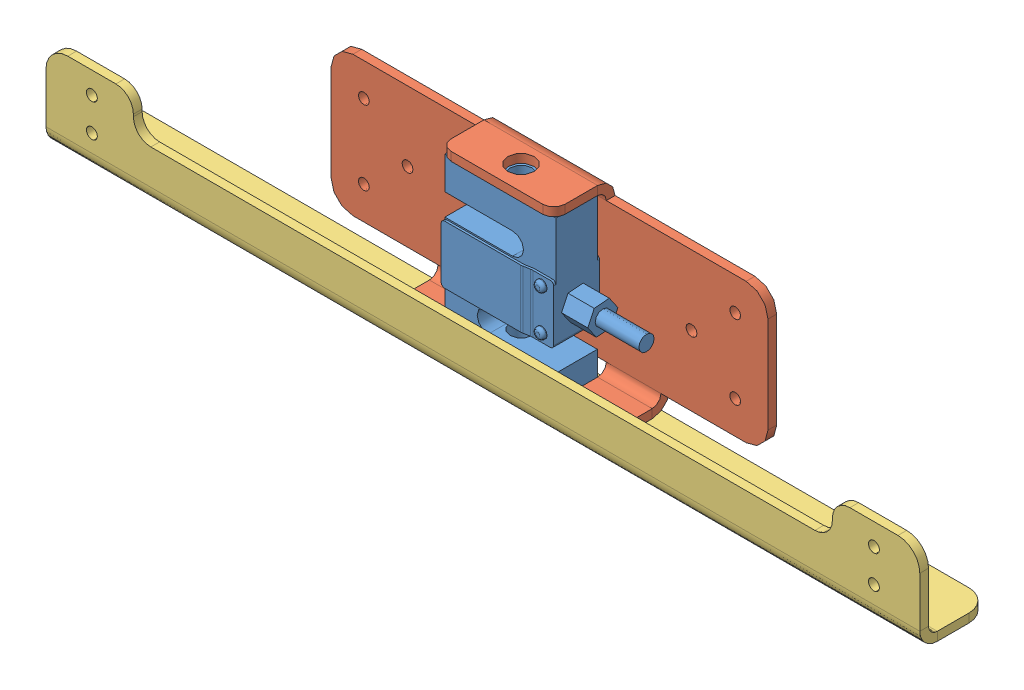
SolidWorks assembly WallBench - Assembly Option 2, configuration Default. Lengths in mm.
Overall size (400 84.5 34.5).
9 component instances, 8 part files, 27 mates.
Components (placement in the parent):
- WallBench - Frame-1: WallBench - Frame [Default] at (-902.6231 586.6756 0) size (560 360 30) (hidden)
- WallBench - Galga-1: WallBench - Galga [Default] at (-902.6231 588.4256 7.5) x (1 0 0) z (0 -1 0) size (82.8 24.7 76.5)
- WallBench - Moving wall-1: WallBench - Moving wall [Default] at (-903.6457 587.3832 38.7366) x (1 0 0) z (0 1 0) size (495 10 295) (hidden)
- Fingerboard-1: Fingerboard [Default] at (-1104.1457 587.3832 58.7366) size (400 99 40) (hidden)
- Tornillo_M12-1: Tornillo_M12 [Default] at (-902.6231 638.6756 17) x (0.845145 0 -0.534536) z (-0.534536 0 -0.845145) size (23.08 23 20.45) (hidden)
- Wall-1: Wall [Default] at (-902.6231 586.6756 -10) x (1 0 0) z (0 -1 0) size (2000 10 1000) (hidden)
- WallBench - Main supoport Option 2-1: WallBench - Main supoport Option 2 [Default] at (-902.6231 590.6756 4) x (1 0 0) z (0 -1 0) size (200 28 80)
- Tornillo_M12-2: Tornillo_M12 [Default] at (-902.6231 534.9122 15) x (0.040349 0 -0.999186) z (0.999186 0 0.040349) size (23.08 23 20.45) (hidden)
- WallBench - L Support-1: WallBench - L Support [Default] at (-902.6231 550.1756 34.75) size (400 41 32.5)
Mates (geometry in assembly coordinates):
- Coincidente1: coincident anti-aligned: plane of WallBench - Frame-1 through (-902.6231 586.6756 0) normal (0 0 -1); plane of assembly through (0 0 0) normal (0 0 1)
- Coincidente2: coincident anti-aligned: plane of WallBench - Frame-1 through (-902.6231 586.6756 0) normal (0 0 -1); plane of Wall-1 through (-902.6231 586.6756 0) normal (0 0 1)
- Distancia1: distance = 320 mm aligned: plane of WallBench - Frame-1 through (-1182.6231 766.6756 30) normal (0 1 0); plane of Wall-1 through (-1902.6231 1086.6756 0) normal (0 1 0)
- Coincidente4: coincident anti-aligned: plane of Wall-1 through (-902.6231 586.6756 0) normal (0 0 1); plane of WallBench - Main supoport Option 2-1 through (-923.6231 645.6756 0) normal (0 0 -1)
- Coincidente5: coincident anti-aligned: plane of WallBench - Galga-1 through (-928.0231 626.6756 26.5) normal (0 1 0); plane of WallBench - Main supoport Option 2-1 through (-923.6231 626.6756 23) normal (0 -1 0)
- Paralelo1: parallel aligned: plane of WallBench - Galga-1 through (-908.2231 570.1756 26.5) normal (0 0 1); plane of WallBench - Main supoport Option 2-1 through (-923.6231 630.6756 28) normal (0 0 1)
- Concéntrica3: concentric anti-aligned: cylinder of WallBench - Galga-1 through (-902.6231 626.6766 17) axis (0 -1 0) radius 5; cylinder of ? through (-902.6231 536.9122 15) axis (0 1 0) radius 6
- Coincidente6: coincident anti-aligned: plane of WallBench - Galga-1 through (-928.0231 550.1756 26.5) normal (0 -1 0); plane of ? through (-1092.6231 546.9122 55) normal (0 1 0)
- Paralelo2: parallel aligned: plane of WallBench - Galga-1 through (-908.2231 570.1756 26.5) normal (0 0 1); plane of ? through (-1092.6231 574.3501 28.7366) normal (0 0 1)
- Coincidente8: coincident: plane of ? through (-1092.6231 574.3501 28.7366) normal (0 0 1); plane of WallBench - Moving wall-1 through (-903.6457 587.3832 28.7366) normal (0 0 -1)
- Coincidente9: coincident anti-aligned: plane of WallBench - Moving wall-1 through (-903.6457 587.3832 38.7366) normal (0 0 1); plane of Fingerboard-1 through (-704.1457 537.8832 38.7366) normal (0 0 -1)
- Concéntrica4: concentric anti-aligned: cylinder of WallBench - Galga-1 through (-902.6231 550.1746 17) axis (0 1 0) radius 5; cylinder of WallBench - Main supoport Option 2-1 through (-902.6231 630.6766 17) axis (0 -1 0) radius 6
- Concéntrica5: concentric anti-aligned: cylinder of Tornillo_M12-1 through (-902.6231 615.6756 17) axis (0 1 0) radius 6; cylinder of WallBench - Main supoport Option 2-1 through (-902.6231 630.6766 17) axis (0 -1 0) radius 6
- Coincidente10: coincident anti-aligned: plane of Tornillo_M12-1 through (-902.6231 630.6756 17) normal (0 -1 0); plane of WallBench - Main supoport Option 2-1 through (-923.6231 630.6756 23) normal (0 1 0)
- Paralelo3: parallel aligned: plane of Tornillo_M12-1 through (-892.6231 630.6756 11.2265) normal (1 0 0); plane of WallBench - Main supoport Option 2-1 through (-876.6231 630.6756 0) normal (1 0 0)
- Concéntrica7: concentric: cylinder of ? through (-902.6231 536.9122 15) axis (0 1 0) radius 6; cylinder of Tornillo_M12-2 through (-902.6231 557.9122 15) axis (0 -1 0) radius 6
- Coincidente12: coincident: plane of ? through (-1092.6231 542.9122 55) normal (0 -1 0); plane of Tornillo_M12-2 through (-902.6231 542.9122 15) normal (0 1 0)
- Perpendicular1: perpendicular: plane of ? through (-1092.6231 574.3501 28.7366) normal (0 0 1); plane of Tornillo_M12-2 through (-892.6231 542.9122 20.7735) normal (1 0 0)
- Distancia2: distance = 720 mm aligned: plane of WallBench - Frame-1 through (-1182.6231 766.6756 30) normal (-1 0 0); plane of Wall-1 through (-1902.6231 1086.6756 0) normal (-1 0 0)
- Distancia5: distance = 150 mm anti-aligned: plane of WallBench - Frame-1 through (-1152.6231 736.6756 30) normal (1 0 0); plane of WallBench - Main supoport Option 2-1 through (-1002.6231 612.6756 0) normal (-1 0 0)
- Distancia6: distance = 114 mm anti-aligned: plane of WallBench - Main supoport Option 2-1 through (-992.6231 622.6756 0) normal (0 1 0); plane of WallBench - Frame-1 through (-1152.6231 736.6756 30) normal (0 -1 0)
- Distancia7: distance = 98 mm aligned: plane of Fingerboard-1 through (-704.1457 636.8832 38.7366) normal (0 1 0); plane of WallBench - Moving wall-1 through (-1151.1457 734.8832 28.7366) normal (0 1 0)
- Distancia8: distance = 47 mm aligned: plane of Fingerboard-1 through (-1104.1457 626.8832 68.7366) normal (-1 0 0); plane of WallBench - Moving wall-1 through (-1151.1457 439.8832 28.7366) normal (-1 0 0)
- Coincidente15: coincident: plane of ? through (-1092.6231 574.3501 28.7366) normal (0 0 1); plane of WallBench - Moving wall-1 through (-903.6457 587.3832 28.7366) normal (0 0 -1)
- Concéntrica8: concentric anti-aligned: cylinder of WallBench - Galga-1 through (-902.6231 626.6766 17) axis (0 -1 0) radius 5; cylinder of WallBench - L Support-1 through (-902.6231 540.1756 17) axis (0 1 0) radius 7
- Coincidente16: coincident anti-aligned: plane of WallBench - Galga-1 through (-928.0231 550.1756 26.5) normal (0 -1 0); plane of WallBench - L Support-1 through (-1092.6231 550.1756 57.5) normal (0 1 0)
- Paralelo5: parallel aligned: plane of WallBench - Galga-1 through (-908.2231 570.1756 26.5) normal (0 0 1); plane of WallBench - L Support-1 through (-1092.6231 577.1756 34.5) normal (0 0 1)
